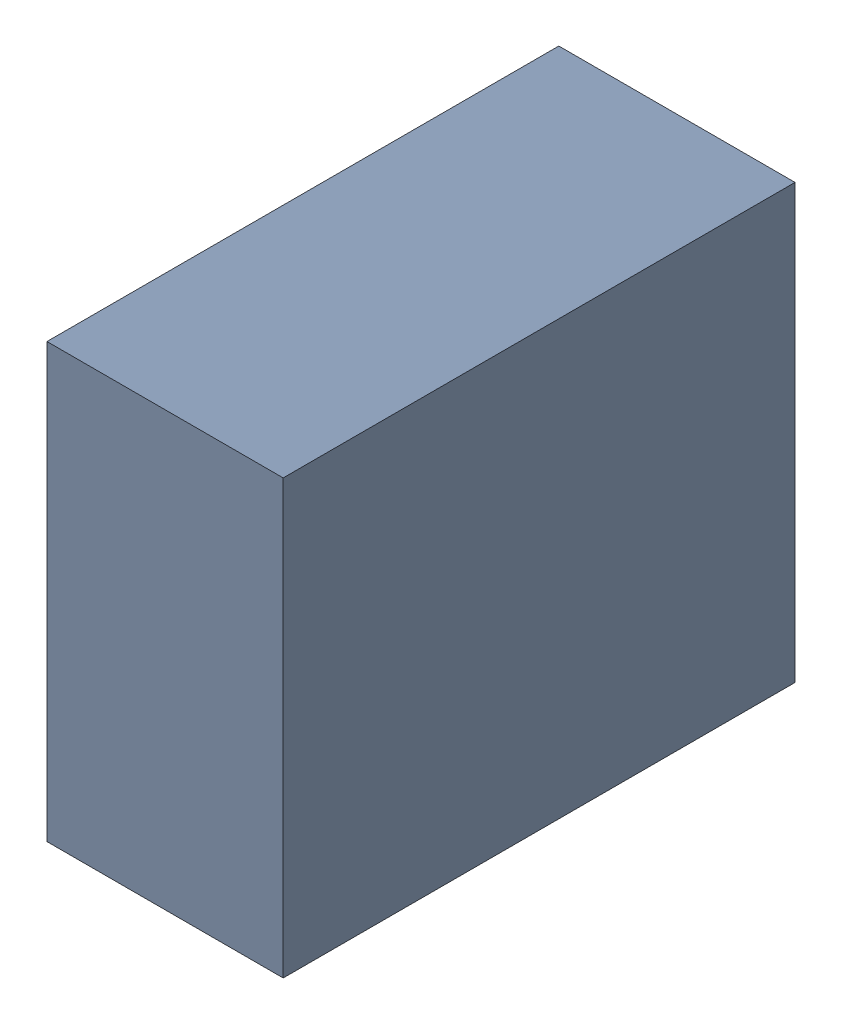
SolidWorks assembly C27_TDA1, configuration Standard. Lengths in mm.
Overall size (0.6 1.1 1.3).
2 component instances, 1 part files, 0 mates.
Components (placement in the parent):
- 885542376-1: 885542376 [Standard] at (1.48 57.54 0) size (0.6 1.1 1.3)
  - Extruded_25-1: Extruded_25 [Standard] at origin size (0.6 1.1 1.3)
